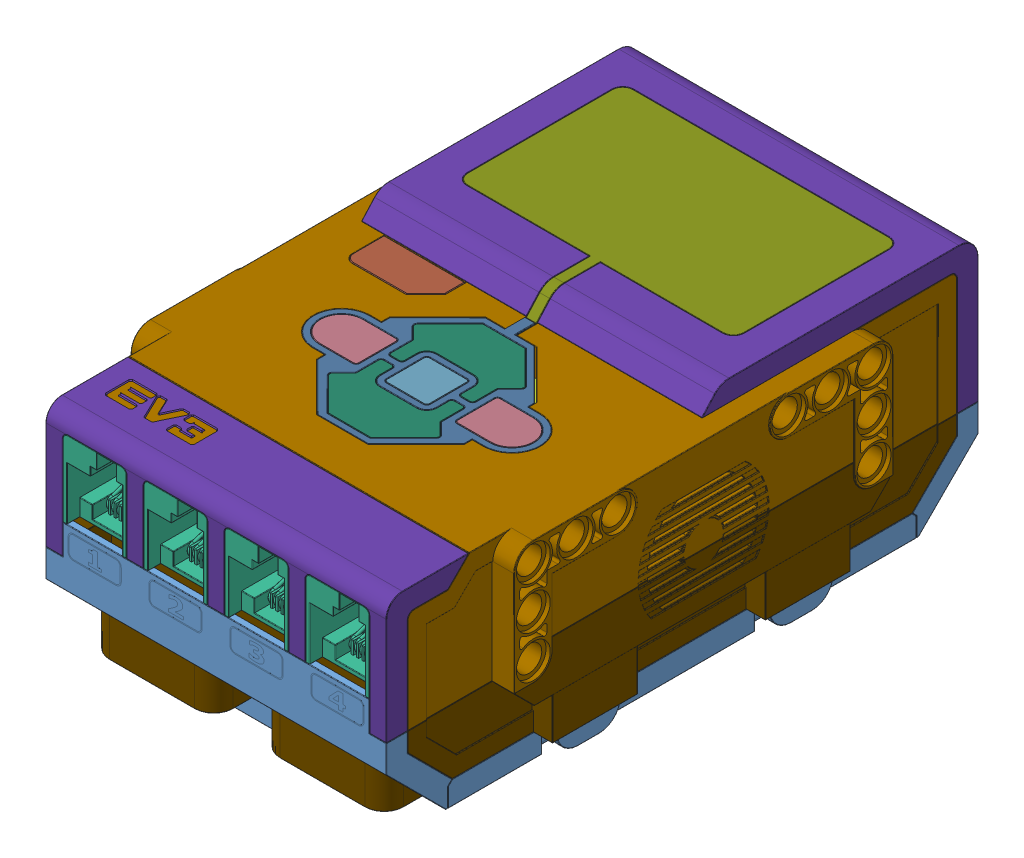
SolidWorks assembly 95646c01, configuration Default. Lengths in mm.
Overall size (72.13 50.8 111.2).
36 component instances, 25 part files, 0 mates.
Components (placement in the parent):
- 95646c01.stp-1: 95646c01.stp [Default] at origin size (72.13 50.8 111.2)
  - 95656.stp-1: 95656.stp [Default] at (0 -35.2 -16) size (68.8 24 88.8)
    - 11142-LtBluishGray.stp-1: 11142-LtBluishGray.stp [Default] at origin size (68.8 20.8 88.8)
    - 11143-LtBluishGray.stp-1: 11143-LtBluishGray.stp [Default] at (-0.4 -0.4 0) size (50 15.2 87.61)
    - 56554-ElectricAlloy.stp-1: 56554-ElectricAlloy.stp [Default] at (-22.8 4.4 -36) x (0 1 0) z (0 0 1) size (5.6 5.52 5.6)
    - 56555-ElectricAlloy.stp-1: 56555-ElectricAlloy.stp [Default] at (-20.8 4.4 36.4) x (0 0 -1) z (-1 0 0) size (9.6 8.8 0.8)
    - 11177-TransGeen.stp-1: 11177-TransGeen.stp [Default] at (9.6 -8 41.6) x (1 0 0) z (0 -1 0) size (3.2 5.6 3.2)
    - 11177-TransRed.stp-1: 11177-TransRed.stp [Default] at (14.8 -8 41.6) x (1 0 0) z (0 -1 0) size (3.2 5.6 3.2)
    - 11186-Black.stp-1: 11186-Black.stp [Default] at (0 0.8 40) x (0 1 0) z (1 0 0) size (7.2 7.2 4.8)
    - u9208.stp-1: u9208.stp [Default] at (21.6 4.4 36.8) x (1 0 0) z (0 0 -1) size (3.2 8.8 3.2)
    - u9208.stp-2: u9208.stp [Default] at (21.6 4.4 -40) x (1 0 0) z (0 0 -1) size (3.2 8.8 3.2)
    - u9208.stp-3: u9208.stp [Default] at (21.6 4.4 0) x (1 0 0) z (0 0 -1) size (3.2 8.8 3.2)
    - u9208.stp-4: u9208.stp [Default] at (-20.8 4.4 28) x (1 0 0) z (0 0 -1) size (3.2 8.8 3.2)
    - u9208.stp-5: u9208.stp [Default] at (-20.8 4.4 -27.6) x (1 0 0) z (0 0 -1) size (3.2 8.8 3.2)
  - 99141p01-White.stp-1: 99141p01-White.stp [Default] at origin size (72.13 26.01 104.41)
  - 11026-TransClear.stp-1: 11026-TransClear.stp [Default] at (0 -2.6 0) size (42.56 5.2 35.4)
  - 11030-LtBluishGray.stp-1: 11030-LtBluishGray.stp [Default] at (-20 -2.5473 -15.88) size (15.28 5.2 7.44)
  - 11036-LCD.stp-1: 11036-LCD.stp [Default] at (0 1.999 -45.7343) size (52 1.6 40)
  - 99145-LtBluishGray.stp-1: 99145-LtBluishGray.stp [Default] at (-16 -2.6 0) size (10.88 5.2 8.16)
  - 99145-LtBluishGray.stp-2: 99145-LtBluishGray.stp [Default] at (16 -2.6 0) x (-1 0 0) z (0 0 -1) size (10.88 5.2 8.16)
  - 99146-LtBluishGray.stp-1: 99146-LtBluishGray.stp [Default] at (0 -2.6 0) size (8.16 5.2 8.16)
  - 99147-LtBluishGray.stp-1: 99147-LtBluishGray.stp [Default] at (0 -2.6 7.98) x (-1 0 0) z (0 0 -1) size (20.74 5.2 14)
  - 99147-LtBluishGray.stp-2: 99147-LtBluishGray.stp [Default] at (0 -2.6 -7.98) size (20.74 5.2 14)
  - 99148p01-TransClear.stp-1: 99148p01-TransClear.stp [Default] at (0 2.8 -47.2) size (52 8 43.2)
  - 99141s01-LtBluishGray.stp-1: 99141s01-LtBluishGray.stp [Default] at (0 0 2.2) size (64 27.2 111.2)
  - 11025-White.stp-1: 11025-White.stp [Default] at (0 -26.8 -16) size (71.6 22 103.2)
  - 11025s02-LtBluishGray.stp-1: 11025s02-LtBluishGray.stp [Default] at (0 -23.2 -16) size (64 22 111.2)
  - 11032-Black.stp-1: 11032-Black.stp [Default] at (-27.6 -14.6 -32) x (0 0 1) z (-1 0 0) size (14.4 6 14.4)
  - 11033-Black.stp-1: 11033-Black.stp [Default] at (23.2 -15.6 -68.8) x (-1 0 0) z (0 0 -1) size (8.2 4.2 10)
  - 11034-Black.stp-1: 11034-Black.stp [Default] at (-34.8 -16.6 -12) x (0 0 1) z (-1 0 0) size (14.4 2 15.2)
  - 11035-LtBluishGray.stp-1: 11035-LtBluishGray.stp [Default] at (-6 -10.8 -71.6) x (-1 0 0) z (0 0 -1) size (45.6 14.56 14.4)
  - 54732b-LtBluishGray.stp-1: 54732b-LtBluishGray.stp [Default] at (-22.8 -10.8 39.6) size (12 14.56 14.4)
  - 54732b-LtBluishGray.stp-2: 54732b-LtBluishGray.stp [Default] at (-7.6 -10.8 39.6) size (12 14.56 14.4)
  - 54732b-LtBluishGray.stp-3: 54732b-LtBluishGray.stp [Default] at (7.6 -10.8 39.6) size (12 14.56 14.4)
  - 54732b-LtBluishGray.stp-4: 54732b-LtBluishGray.stp [Default] at (22.8 -10.8 39.6) size (12 14.56 14.4)
  - 97622-PCB.stp-1: 97622-PCB.stp [Default] at (0 -6 0) size (48 1.6 40)
